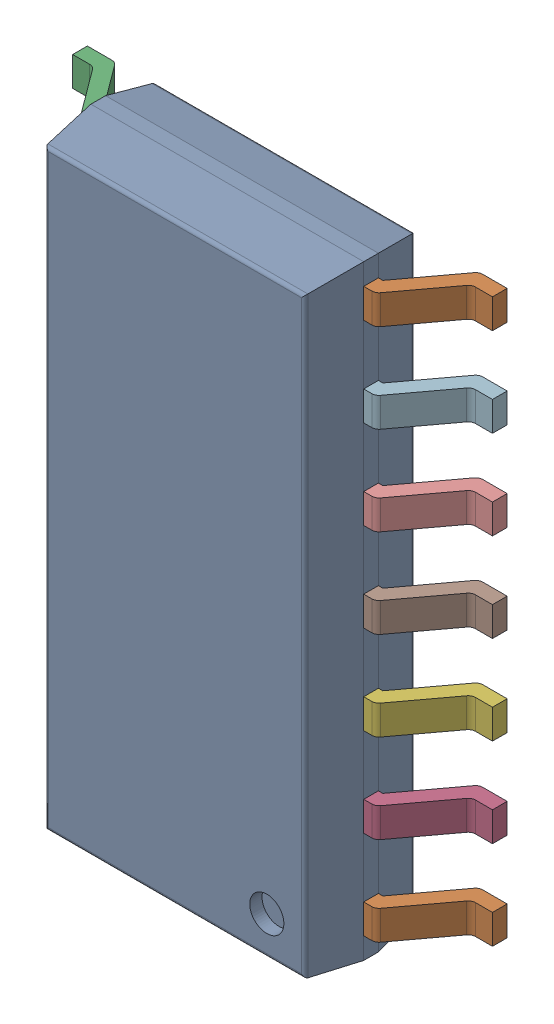
SolidWorks assembly IC11_IC103_1.step, configuration Default. Lengths in mm.
Overall size (6 8.65 1.75).
3 component instances, 2 part files, 0 mates.
Components (placement in the parent):
- 6348793888_1.step-11: 6348793888_1.step [Default] at (488.13 251.303 0) x (-1 0 0) z (0 0 1) size (6 8.65 1.75)
  - Body-16_1.step-54: Body-16_1.step [Default] at origin size (3.9 8.65 1.57)
  - PinsArrayLR-17_1.step-54: PinsArrayLR-17_1.step [Default] at origin size (6 8.04 1)
